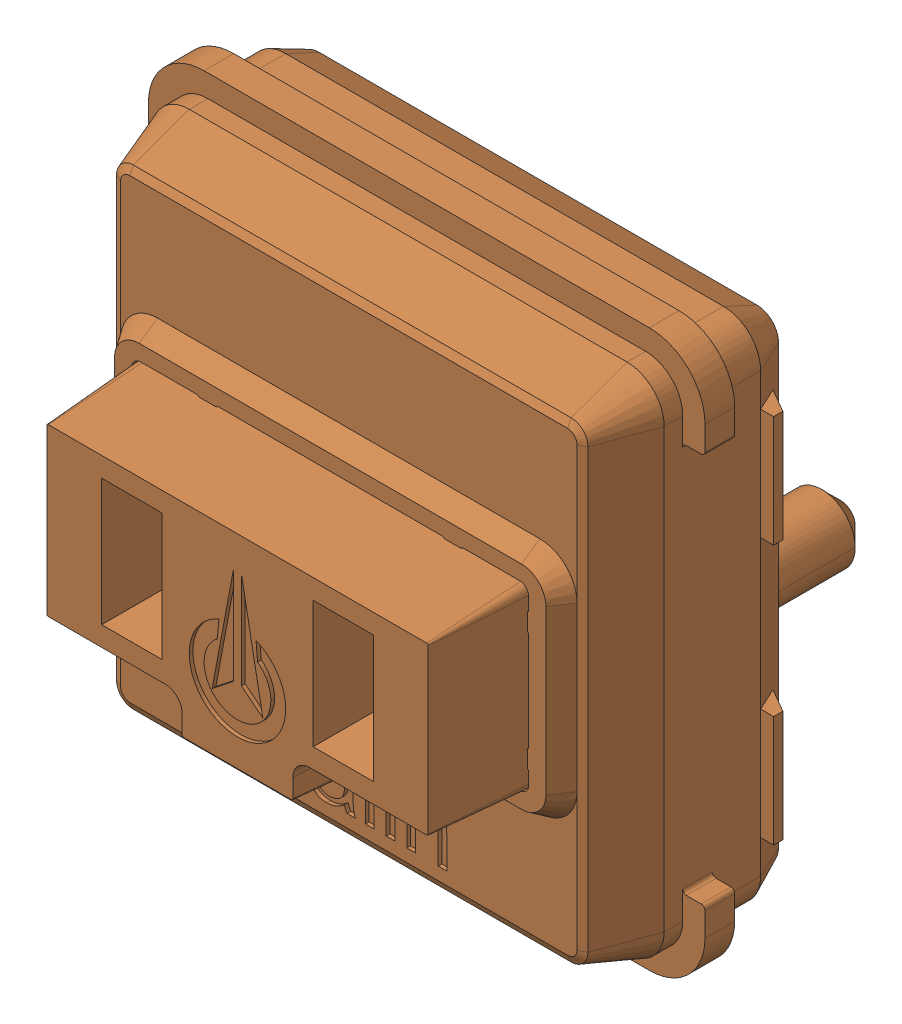
SolidWorks assembly SW1_1.step, configuration Default. Lengths in mm.
Overall size (15 15 11.1).
2 component instances, 2 part files, 0 mates.
Components (placement in the parent):
- WS2812-2020_1.step-3: WS2812-2020_1.step [Default] at (496.489 231.0345 0.3) x (1 0 0) z (0 -1 0) size (2.2 0.86 2)
- Kailh LP Choc Burnt Orange_1.step-3: Kailh LP Choc Burnt Orange_1.step [Default] at (496.3824 226.3933 2.7) x (0 -1 0) z (-1 0 0) size (15 11.1 15)
